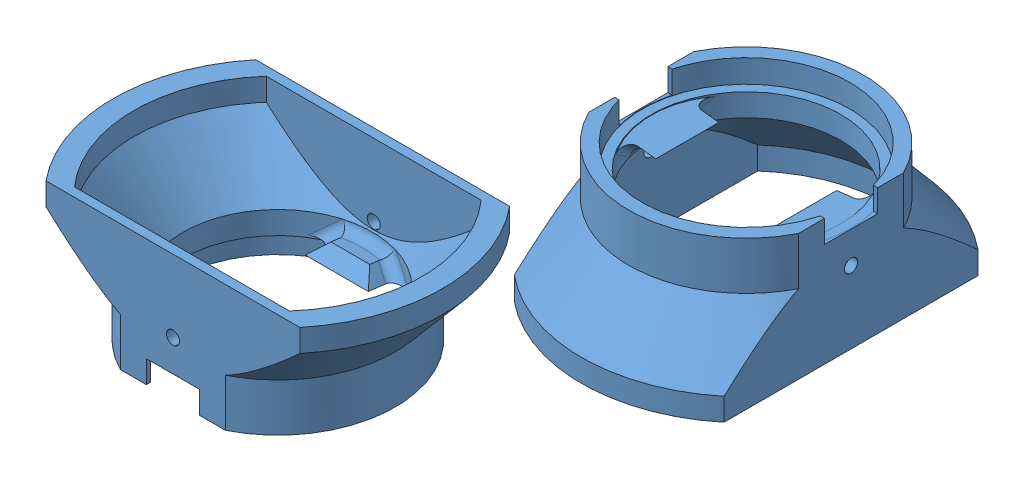
SolidWorks assembly Assem1, configuration Default. Lengths in mm.
Overall size (101.84 28 121.44).
2 component instances, 1 part files, 5 mates.
Components (placement in the parent):
- preferenceV2_dispenser_funnel-1: preferenceV2_dispenser_funnel [Symmetric] at (0 2 0) size (73 28 46.5)
- preferenceV2_dispenser_funnel-2: preferenceV2_dispenser_funnel [Symmetric] at (42.0915 26 -61.6931) x (0 0 -1) z (-1 0 0) size (73 28 46.5)
Mates (geometry in assembly coordinates):
- Coincident1: coincident aligned: plane of preferenceV2_dispenser_funnel-1 through (0 0 0) normal (0 -1 0); plane of preferenceV2_dispenser_funnel-2 through (42.0915 0 -61.6931) normal (0 -1 0)
- Perpendicular2: perpendicular: plane of preferenceV2_dispenser_funnel-1 through (-28.1369 28 -23.25) normal (0 0 -1); plane of preferenceV2_dispenser_funnel-2 through (18.8415 0 -33.5562) normal (-1 0 0)
- Coincident4: coincident aligned: plane of preferenceV2_dispenser_funnel-1 through (0 2 0) normal (1 0 0)
- Coincident5: coincident anti-aligned: plane of preferenceV2_dispenser_funnel-1 through (0 0 0) normal (0 -1 0)
- Coincident6: coincident aligned: plane of preferenceV2_dispenser_funnel-1 through (0 2 0) normal (0 0 1)
